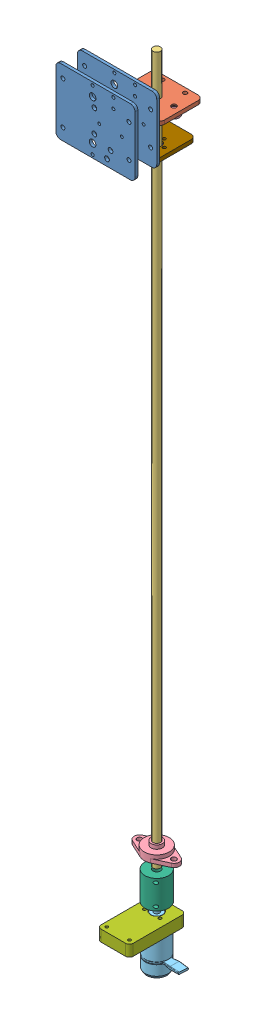
SolidWorks assembly 装配体1, configuration 默认. Lengths in mm.
Overall size (98.89 849.38 90.5).
12 component instances, 10 part files, 16 mates.
Components (placement in the parent):
- 21RM_飞镖.02.01.0033(侧加固板)-3: 21RM_飞镖.02.01.0033(侧加固板) [EXTRA] at (-139.0395 687.957 26) x (-1 0 0) z (0 -1 0) size (84 3 70)
- 21RM_飞镖.02.01.0033(侧加固板)-4: 21RM_飞镖.02.01.0033(侧加固板) [EXTRA] at (-139.0395 687.957 49) x (-1 0 0) z (0 -1 0) size (84 3 70)
- 21RM_飞镖.02.01.0007(卧式轴承座固定板)-2: 21RM_飞镖.02.01.0007(卧式轴承座固定板) [小孔] at (-98.5395 694.8922 0) x (-1 0 0) z (0 0 1) size (81.38 4 46)
- 21RM_飞镖.02.01.0006(装填丝杆).-1: 21RM_飞镖.02.01.0006(装填丝杆). [600] at (-98.5395 -11.9115 0) x (0.987598 0 -0.157006) z (0.157006 0 0.987598) size (8 750 8)
- 21RM_飞镖.02.01.0008(菱形轴承座)-1: 21RM_飞镖.02.01.0008(菱形轴承座) [默认] at (-98.5395 -0.4911 0) size (47.8 12 26.5)
- 21RM_飞镖.02.01.0008(菱形轴承座)-2: 21RM_飞镖.02.01.0008(菱形轴承座) [默认] at (-98.5395 690.8922 0) x (1 0 0) z (0 0 -1) size (47.8 12 26.5)
- 21RM_飞镖.02.01.0057(2006电机)-1: 21RM_飞镖.02.01.0057(2006电机) [默认] at (-98.5395 -107.2911 0) x (0.998128 0 0.061157) z (-0.061157 0 0.998128) size (42.4 71.8 24.4)
- 21RM_飞镖.02.01.0011(D25L30平行线联轴器(6对8))-1: 21RM_飞镖.02.01.0011(D25L30平行线联轴器(6对8)) [默认] at (-98.5395 -44.6071 0) x (0 1 0) z (-0.130574 0 0.991439) size (30 25 25)
- 2006连接件-1: 2006连接件 [默认] at (-98.5395 -53.4911 16) x (-1 0 0) z (0 0 1) size (34 12 60)
- 零件1^装配体1-1: 零件1^装配体1 [默认] at origin (virtual)
- 21RM_飞镖.02.01.0012(丝杆螺母)-1: 21RM_飞镖.02.01.0012(丝杆螺母) [默认] at (-98.5395 647.7386 0) x (0 0 -1) z (-1 0 0) size (22 10.5 22)
- 5_12_1-11-1: 5_12_1-11 [可转动] at (-153.5395 647.7386 -5) size (83 4 62)
Mates (geometry in assembly coordinates):
- 距离2: distance = 20 mm anti-aligned: plane of 21RM_飞镖.02.01.0033(侧加固板)-3 through (-139.0395 687.957 26) normal (0 0 1); plane of 21RM_飞镖.02.01.0033(侧加固板)-4 through (-139.0395 687.957 46) normal (0 0 -1)
- 重合7: coincident aligned: circle of 21RM_飞镖.02.01.0033(侧加固板)-3; cylinder of 21RM_飞镖.02.01.0033(侧加固板)-4 through (-117.5395 709.207 46) axis (0 0 1) radius 3.5
- 同心6: concentric aligned: cylinder of 21RM_飞镖.02.01.0033(侧加固板)-3 through (-117.5395 666.707 23) axis (0 0 1) radius 3.5; cylinder of 21RM_飞镖.02.01.0033(侧加固板)-4 through (-117.5395 666.707 46) axis (0 0 1) radius 3.5
- 同心17: concentric anti-aligned: cylinder of 21RM_飞镖.02.01.0057(2006电机)-1 through (-98.5395 -39.4911 0) axis (0 1 0) radius 1.25; cylinder of 21RM_飞镖.02.01.0011(D25L30平行线联轴器(6对8))-1 through (-98.5395 -163.5498 0) axis (0 -1 0) radius 3
- 同心18: concentric aligned: circle of 21RM_飞镖.02.01.0006(装填丝杆).-1; circle of 21RM_飞镖.02.01.0057(2006电机)-1
- 同心19: concentric anti-aligned: cylinder of 21RM_飞镖.02.01.0007(卧式轴承座固定板)-2 through (-98.5395 690.8922 0) axis (0 1 0) radius 4.15; cylinder of 21RM_飞镖.02.01.0011(D25L30平行线联轴器(6对8))-1 through (-98.5395 -163.5498 0) axis (0 -1 0) radius 4
- 同心20: concentric aligned: cylinder of 21RM_飞镖.02.01.0008(菱形轴承座)-1 through (-98.5395 7.5089 0) axis (0 -1 0) radius 4; cylinder of 21RM_飞镖.02.01.0011(D25L30平行线联轴器(6对8))-1 through (-98.5395 -163.5498 0) axis (0 -1 0) radius 4
- 重合15: coincident anti-aligned: plane of 21RM_飞镖.02.01.0007(卧式轴承座固定板)-2 through (-98.5395 690.8922 0) normal (0 -1 0); plane of 21RM_飞镖.02.01.0008(菱形轴承座)-2 through (-98.5395 690.8922 0) normal (0 1 0)
- 同心22: concentric anti-aligned: circle of 21RM_飞镖.02.01.0007(卧式轴承座固定板)-2; cylinder of 21RM_飞镖.02.01.0008(菱形轴承座)-2 through (-98.5395 682.8922 0) axis (0 1 0) radius 4
- 同心23: concentric aligned: cone of 21RM_飞镖.02.01.0007(卧式轴承座固定板)-2 through (-116.7895 690.8922 0) axis (0 1 0); cylinder of 21RM_飞镖.02.01.0008(菱形轴承座)-2 through (-116.7895 686.8922 0) axis (0 1 0) radius 2.65
- 同心24: concentric aligned: cylinder of 21RM_飞镖.02.01.0057(2006电机)-1 through (-98.5395 -39.4911 0) axis (0 -1 0) radius 3; cylinder of 2006连接件-1 through (-98.5395 -56.4911 0) axis (0 -1 0) radius 12.5
- 重合16: coincident anti-aligned: plane of 21RM_飞镖.02.01.0057(2006电机)-1 through (-98.5395 -56.4911 0) normal (0 1 0); circle of 2006连接件-1
- 同心34: concentric anti-aligned: cylinder of 21RM_飞镖.02.01.0006(装填丝杆).-1 through (-98.5395 738.0885 0) axis (0 -1 0) radius 4; circle of 21RM_飞镖.02.01.0031(飞镖装填支撑)-1
- 重合25: coincident anti-aligned: plane of 21RM_飞镖.02.01.0012(丝杆螺母)-1 through (-98.5395 647.7386 0) normal (0 1 0); plane of 5_12_1-11-1 through (-153.5395 647.7386 -5) normal (0 -1 0)
- 同心35: concentric anti-aligned: cylinder of 21RM_飞镖.02.01.0012(丝杆螺母)-1 through (-98.5395 644.2386 -8) axis (0 -1 0) radius 1.25; cylinder of 5_12_1-11-1 through (-98.5395 647.7386 -8) axis (0 1 0) radius 1.6
- 同心36: concentric anti-aligned: cylinder of 21RM_飞镖.02.01.0012(丝杆螺母)-1 through (-98.5395 649.7386 0) axis (0 -1 0) radius 4; cylinder of 5_12_1-11-1 through (-98.5395 647.7386 0) axis (0 1 0) radius 5.1
